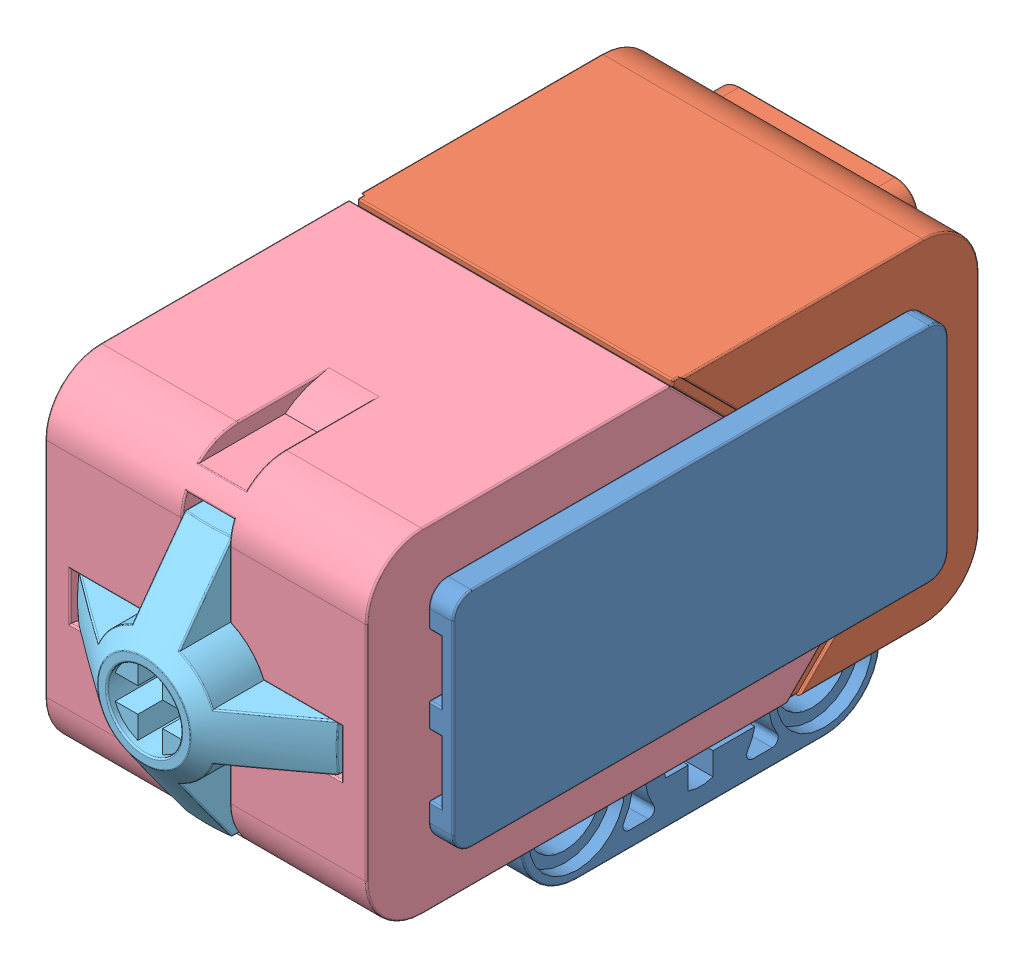
SolidWorks assembly EV3 Touch Sensor, configuration Default. Lengths in mm.
Overall size (24 31.05 43.62).
7 component instances, 5 part files, 0 mates.
Components (placement in the parent):
- 95648.stp-1: 95648.stp [Default] at origin size (24 31.05 43.62)
  - 99385c01.stp-1: 99385c01.stp [Default] at origin size (24 31.05 39.62)
    - 99377-LtBluishGray.stp-1: 99377-LtBluishGray.stp [Default] at origin size (24 29.6 38)
    - 99376-White.stp-1: 99376-White.stp [Default] at (0 0.44 -14.2) size (22.3 23.6 19.62)
    - 54732b-LtBluishGray.stp-1: 54732b-LtBluishGray.stp [Default] at (0 2.04 -20.2) x (-1 0 0) z (0 0 -1) size (12 14.56 14.4)
    - 99385-LtBluishGray.stp-1: 99385-LtBluishGray.stp [Default] at (0 0.44 13.8) size (22.4 21.61 30.66)
  - 99386-Red.stp-1: 99386-Red.stp [Default] at (0 -0.36 15.4) size (18.23 16.99 14.8)
